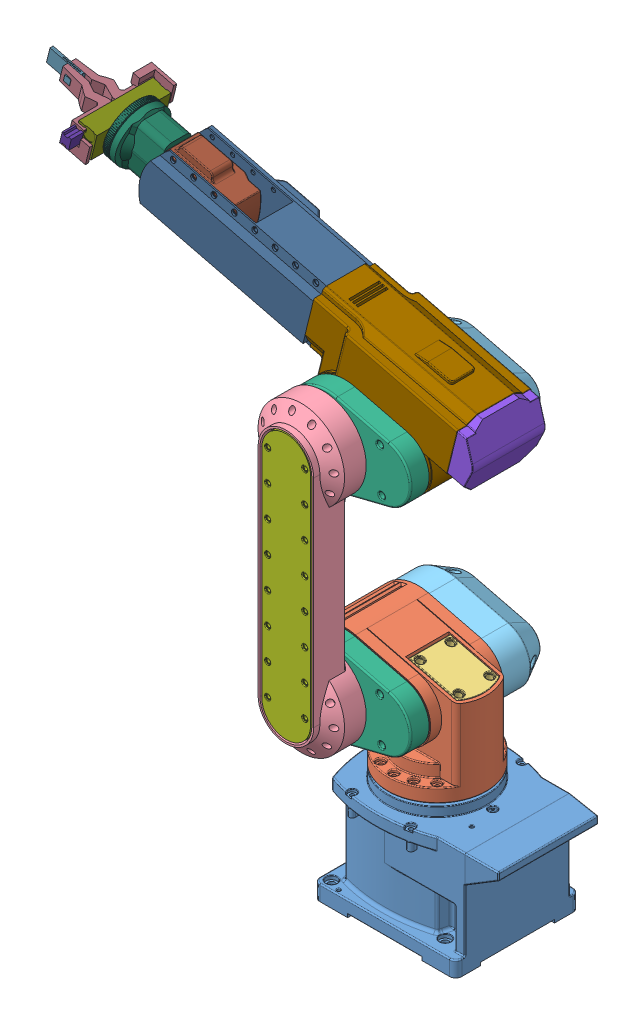
SolidWorks assembly Movable_assembly, configuration Default. Lengths in mm.
Overall size (813.38 886.02 303.42).
21 component instances, 17 part files, 61 mates.
Components (placement in the parent):
- Base-1: Base [Default] at (40.6048 41.5807 232.9888) size (280 185 200)
- Joint_1-1: Joint_1 [Default] at (58.3613 353.1317 232.9888) size (240 189 160)
- Joint_1_top_cap-1: Joint_1_top_cap [Default] at (60.6594 336.5807 232.9888) x (1 0 0) z (0 1 0) size (91.2 70 52.23)
- Joint_2-1: Joint_2 [Default] at (-31.634 665.5321 237.1035) x (0 -0.999953 -0.009698) z (0.003009 -0.009698 0.999948) size (490.3 140.11 64.56)
- Joint_1_right_cap-1: Joint_1_right_cap [Default] at (58.5861 41.5807 232.9888) x (0.999948 0.000764 -0.010154) z (0.010154 0.000008 0.999948) size (207.37 139.74 83.67)
- Joint_1_left_cap-1: Joint_1_left_cap [Default] at (58.5861 41.5807 232.9888) x (0.999948 0.000764 -0.010154) z (0.010154 0.000008 0.999948) size (205.37 137 45.97)
- joint_2_cap-1: joint_2_cap [Default] at (-285.7576 162.4328 232.9888) x (0.296333 -0.955031 -0.010154) z (0.003009 -0.009698 0.999948) size (415.27 184.72 18.75)
- Joint_3_cap^industry_robot_arm_3-1: Joint_3_cap^industry_robot_arm_3 [Default] at (285.08 198.5959 233.9888) x (0.970756 -0.239852 -0.010154) z (0.009858 -0.002436 0.999948) size (35.03 98.08 118.33)
- Joint_1_left_cap-2: Joint_1_left_cap [Default] at (58.5861 391.5643 232.9888) x (0.999948 0.000764 -0.010154) z (0.010154 0.000008 0.999948) size (205.37 137 45.97)
- Joint_1_right_cap-2: Joint_1_right_cap [Default] at (58.5861 391.5643 232.9888) x (0.999948 0.000764 -0.010154) z (0.010154 0.000008 0.999948) size (207.37 139.74 83.67)
- Joint_3-1: Joint_3 [Default] at (14.2411 648.346 236.7544) x (0.970756 -0.239852 -0.010154) z (0.009858 -0.002436 0.999948) size (270.42 212 122.27)
- Joint_3_front^industry_robot_arm_3-1: Joint_3_front^industry_robot_arm_3 [Default] at (-188.0196 914.7128 232.7268) x (0.970807 -0.239864 0) z (0 0 -1) size (280 99.67 120)
- joint_4^industry_robot_arm_3-1: joint_4^industry_robot_arm_3 [Default] at (-600.5154 840.3358 232.7268) x (-0.970807 0.239864 0) z (0 0 -1) size (126.86 92 60)
- Joint_3_top_cap^industry_robot_arm_3-1: Joint_3_top_cap^industry_robot_arm_3 [Default] at (518.3873 1141.5812 232.7268) x (0.970807 -0.239864 0) z (0 0 -1) size (97 20 57)
- Gripper_left^industry_robot_arm_3-1: Gripper_left^industry_robot_arm_3 [Default] at (467.2414 797.4566 88.5598) x (0.970807 -0.239864 0) z (0 0 -1) size (105.79 39 65)
- Gripper_right_grip^industry_robot_arm_3-1: Gripper_right_grip^industry_robot_arm_3 [Default] at (-1362.2348 1602.1194 -1819.7851) x (0.954279 -0.23578 0.183739) z (0.178375 -0.044072 -0.982975) size (52.87 24 20.92)
- joint_4_front^industry_robot_arm_3-1: joint_4_front^industry_robot_arm_3 [Default] at (-385.304 920.4982 389.4249) x (0 0 1) z (0.970807 -0.239864 0) size (88 88 70)
- joint_4_super_front^industry_robot_arm_3-1: joint_4_super_front^industry_robot_arm_3 [Default] at (-457.7741 793.9494 -121.3208) x (0 0 1) z (-0.970807 0.239864 0) size (120 40 40)
- joint_4_super_front_middle^industry_robot_arm_3-1: joint_4_super_front_middle^industry_robot_arm_3 [Default] at (-435.1377 966.8623 647.8138) x (0 0 -1) z (-0.970807 0.239864 0) size (160 18 25)
- Gripper_left^industry_robot_arm_3-2: Gripper_left^industry_robot_arm_3 [Default] at (399.422 522.9698 371.8138) x (0.970807 -0.239864 0) z (0 0 1) size (105.79 39 65)
- Gripper_right_grip^industry_robot_arm_3-2: Gripper_right_grip^industry_robot_arm_3 [Default] at (-1594.2874 662.9283 2280.1586) x (0.954279 -0.23578 -0.183739) z (0.178375 -0.044072 0.982975) size (52.87 24 20.92)
Mates (geometry in assembly coordinates):
- Coincident1: coincident anti-aligned: plane of Base-1 through (58.3613 216.5807 232.9888) normal (0 1 0); plane of Joint_1-1 through (58.3613 216.5807 232.9888) normal (0 -1 0)
- Concentric1: concentric anti-aligned: cylinder of Base-1 through (58.3613 216.5807 232.9888) axis (0 1 0) radius 70; cylinder of Joint_1-1 through (58.3613 242.5807 232.9888) axis (0 -1 0) radius 69
- Coincident2: coincident anti-aligned: plane of Joint_1-1 through (58.3613 336.5807 232.9888) normal (0 1 0); plane of Joint_1_top_cap-1 through (60.6594 336.5807 232.9888) normal (0 -1 0)
- Concentric2: concentric aligned: cylinder of Joint_1-1 through (58.3613 405.5807 232.9888) axis (0 -1 0) radius 75; cylinder of Joint_1_top_cap-1 through (58.3613 490.3724 232.9888) axis (0 -1 0) radius 75.4393
- Parallel1: parallel anti-aligned: plane of Joint_1-1 through (42.1565 405.5807 267.9888) normal (1 0 0); plane of Joint_1_top_cap-1 through (45.9545 490.3724 199.4888) normal (-1 0 0)
- Concentric3: concentric aligned: cylinder of Joint_1-1 through (58.3613 335.5807 272.9888) axis (0 0 -1) radius 48.4134; cylinder of Joint_1_left_cap-1 through (58.3613 335.5807 322.9888) axis (0 0 -1) radius 46.9225
- Concentric4: concentric anti-aligned: cylinder of Joint_1-1 through (58.3613 335.5807 272.9888) axis (0 0 -1) radius 48.4134; cylinder of Joint_1_right_cap-1 through (58.3613 335.5807 92.9888) axis (0 0 1) radius 46.9225
- Coincident4: coincident anti-aligned: plane of Joint_1-1 through (58.3613 353.1317 172.9888) normal (0 0 -1); plane of Joint_1_right_cap-1 through (58.3613 335.5807 172.9888) normal (0 0 1)
- Parallel2: parallel aligned: plane of Joint_1-1 through (65.887 383.5905 272.9888) normal (0.239864 0.970807 0); plane of Joint_1_right_cap-1 through (-14.8877 402.0123 92.9888) normal (0.239864 0.970807 0)
- Coincident5: coincident anti-aligned: plane of Joint_1-1 through (58.3613 353.1317 292.9888) normal (0 0 1); plane of Joint_1_left_cap-1 through (58.3613 335.5807 292.9888) normal (0 0 -1)
- Concentric5: concentric aligned: cylinder of Joint_1-1 through (58.3613 335.5807 272.9888) axis (0 0 -1) radius 48.4134; cylinder of Joint_1_left_cap-1 through (58.3613 335.5807 322.9888) axis (0 0 -1) radius 46.9225
- Parallel3: parallel aligned: plane of Joint_1-1 through (65.887 383.5905 272.9888) normal (0.239864 0.970807 0); plane of Joint_1_left_cap-1 through (69.6164 381.1333 322.9888) normal (0.239864 0.970807 0)
- Coincident6: coincident anti-aligned: plane of Joint_2-1 through (-31.634 335.5119 327.9888) normal (0 0 -1); plane of Joint_1_left_cap-1 through (-31.634 335.5119 327.9888) normal (0 0 1)
- Concentric6: concentric aligned: cylinder of Joint_2-1 through (-31.634 335.5119 337.9888) axis (0 0 -1) radius 30; cylinder of Joint_1_left_cap-1 through (-31.634 335.5119 337.9888) axis (0 0 -1) radius 30
- Concentric7: concentric anti-aligned: cylinder of Joint_2-1 through (-31.634 335.5119 372.9888) axis (0 0 1) radius 42; cylinder of joint_2_cap-1 through (-31.634 335.5119 387.5288) axis (0 0 -1) radius 39.5
- Concentric8: concentric anti-aligned: cylinder of Joint_2-1 through (-31.634 685.4954 372.9888) axis (0 0 1) radius 42; cylinder of joint_2_cap-1 through (-31.634 685.4954 387.5288) axis (0 0 -1) radius 39.5
- Coincident7: coincident anti-aligned: plane of Joint_2-1 through (-31.634 685.4954 372.9888) normal (0 0 1); plane of joint_2_cap-1 through (-31.634 335.5119 372.9888) normal (0 0 -1)
- Concentric9: concentric aligned: cylinder of Joint_2-1 through (-31.634 685.4954 337.9888) axis (0 0 -1) radius 30; cylinder of Joint_1_left_cap-2 through (-31.634 685.4954 337.9888) axis (0 0 -1) radius 30
- Coincident8: coincident anti-aligned: plane of Joint_2-1 through (-31.634 685.4954 327.9888) normal (0 0 -1); plane of Joint_1_left_cap-2 through (-31.634 685.4954 327.9888) normal (0 0 1)
- Coincident9: coincident anti-aligned: plane of Joint_3_cap^industry_robot_arm_3-1 through (153.4742 780.9574 263.176) normal (-0.970807 0.239864 0); plane of Joint_3-1 through (129.8476 685.333 172.9888) normal (0.970807 -0.239864 0)
- Coincident10: coincident aligned: plane of Joint_3_cap^industry_robot_arm_3-1 through (187.8122 774.0184 204.6587) normal (0.239864 0.970807 0); plane of Joint_3-1 through (-35.4705 829.1864 177.9888) normal (0.239864 0.970807 0)
- Coincident11: coincident aligned: plane of Joint_3_cap^industry_robot_arm_3-1 through (185.0538 762.8541 292.9888) normal (0 0 1); plane of Joint_3-1 through (58.3613 685.5642 292.9888) normal (0 0 1)
- Concentric10: concentric anti-aligned: cylinder of Joint_1_left_cap-2 through (58.3613 685.5642 322.9888) axis (0 0 -1) radius 46.9225; cylinder of Joint_3-1 through (58.3613 685.5642 172.9888) axis (0 0 1) radius 46.9225
- Coincident12: coincident anti-aligned: plane of Joint_1_left_cap-2 through (58.3613 685.5642 292.9888) normal (0 0 -1); plane of Joint_3-1 through (58.3613 685.5642 292.9888) normal (0 0 1)
- Concentric11: concentric anti-aligned: cylinder of Joint_1_left_cap-2 through (-31.3184 685.4956 322.9888) axis (0 0 -1) radius 68.5; cylinder of Joint_3-1 through (-31.3184 685.4956 172.9888) axis (0 0 1) radius 68.5
- Concentric12: concentric aligned: cylinder of Joint_1_right_cap-2 through (-31.3184 685.4956 92.9888) axis (0 0 1) radius 68.5; cylinder of Joint_3-1 through (-31.3184 685.4956 172.9888) axis (0 0 1) radius 68.5
- Concentric13: concentric aligned: cylinder of Joint_1_right_cap-2 through (58.3613 685.5642 92.9888) axis (0 0 1) radius 46.9225; cylinder of Joint_3-1 through (58.3613 685.5642 172.9888) axis (0 0 1) radius 46.9225
- Coincident13: coincident anti-aligned: plane of Joint_1_right_cap-2 through (58.3613 685.5642 172.9888) normal (0 0 1); plane of Joint_3-1 through (58.3613 685.5642 172.9888) normal (0 0 -1)
- Coincident19: coincident anti-aligned: plane of Joint_3_front^industry_robot_arm_3-1 through (-218.3075 792.128 232.7268) normal (-0.239864 -0.970807 0); plane of Joint_3_top_cap^industry_robot_arm_3-1 through (394.6276 640.6859 232.7268) normal (0.239864 0.970807 0)
- Distance3: distance = 1.5 mm anti-aligned: plane of Joint_3_front^industry_robot_arm_3-1 through (-212.8637 790.783 262.7268) normal (0.970807 -0.239864 0); plane of Joint_3_top_cap^industry_robot_arm_3-1 through (-216.2047 771.0071 261.2268) normal (-0.970807 0.239864 0)
- Distance4: distance = 1.5 mm anti-aligned: plane of Joint_3_top_cap^industry_robot_arm_3-1 through (-216.2047 771.0071 204.2268) normal (0 0 -1); plane of Joint_3_front^industry_robot_arm_3-1 through (-212.8637 790.783 202.7268) normal (0 0 1)
- Concentric14: concentric anti-aligned: cylinder of Joint_3_front^industry_robot_arm_3-1 through (-326.0038 847.8276 202.7268) axis (0 0 1) radius 30; cylinder of joint_4^industry_robot_arm_3-1 through (-326.0038 847.8276 262.7268) axis (0 0 -1) radius 30
- Coincident22: coincident anti-aligned: plane of Joint_3_front^industry_robot_arm_3-1 through (-481.1136 939.1221 202.7268) normal (0 0 1); plane of joint_4^industry_robot_arm_3-1 through (-600.5154 840.3358 202.7268) normal (0 0 -1)
- Coincident23: coincident anti-aligned: plane of joint_4^industry_robot_arm_3-1 through (-392.0827 788.8368 232.7268) normal (-0.970807 0.239864 0); plane of joint_4_front^industry_robot_arm_3-1 through (-361.0338 914.5016 389.4249) normal (0.970807 -0.239864 0)
- Coincident24: coincident aligned: plane of joint_4^industry_robot_arm_3-1 through (-257.9339 789.8062 202.7268) normal (-0.239864 -0.970807 0); plane of joint_4_front^industry_robot_arm_3-1 through (-379.2847 819.7892 202.7268) normal (-0.239864 -0.970807 0)
- Coincident25: coincident anti-aligned: plane of joint_4^industry_robot_arm_3-1 through (-370.9462 874.3829 247.7268) normal (0 0 1); plane of joint_4_front^industry_robot_arm_3-1 through (-378.1421 845.2587 247.7268) normal (0 0 -1)
- Parallel4: parallel aligned: plane of joint_4^industry_robot_arm_3-1 through (-257.9339 789.8062 202.7268) normal (-0.239864 -0.970807 0); plane of Joint_3_top_cap^industry_robot_arm_3-1 through (389.8303 621.2697 232.7268) normal (-0.239864 -0.970807 0)
- Coincident27: coincident anti-aligned: plane of joint_4_front^industry_robot_arm_3-1 through (-414.4282 927.6941 389.4249) normal (-0.970807 0.239864 0); plane of joint_4_super_front^industry_robot_arm_3-1 through (-448.0661 791.5507 -121.3208) normal (0.970807 -0.239864 0)
- Coincident28: coincident anti-aligned: plane of joint_4_front^industry_robot_arm_3-1 through (-431.5365 858.4512 247.7268) normal (0.239864 0.970807 0); plane of joint_4_super_front^industry_robot_arm_3-1 through (-431.5365 858.4512 247.7268) normal (-0.239864 -0.970807 0)
- Coincident29: coincident anti-aligned: plane of joint_4_front^industry_robot_arm_3-1 through (-431.5365 858.4512 217.7268) normal (0 0 1); plane of joint_4_super_front^industry_robot_arm_3-1 through (-431.5365 858.4512 217.7268) normal (0 0 -1)
- Coincident30: coincident anti-aligned: plane of joint_4_super_front^industry_robot_arm_3-1 through (-466.9968 796.2281 -121.3208) normal (-0.970807 0.239864 0); plane of joint_4_super_front_middle^industry_robot_arm_3-1 through (-425.4296 964.4637 647.8138) normal (0.970807 -0.239864 0)
- Coincident31: coincident anti-aligned: plane of joint_4_super_front^industry_robot_arm_3-1 through (-448.0686 872.8366 227.7268) normal (0.239864 0.970807 0); plane of joint_4_super_front_middle^industry_robot_arm_3-1 through (-448.0686 872.8366 227.7268) normal (-0.239864 -0.970807 0)
- Coincident32: coincident anti-aligned: plane of joint_4_super_front^industry_robot_arm_3-1 through (-445.6699 882.5447 237.7268) normal (0 0 -1); plane of joint_4_super_front_middle^industry_robot_arm_3-1 through (-448.0686 872.8366 237.7268) normal (0 0 1)
- Coincident34: coincident anti-aligned: plane of Gripper_left^industry_robot_arm_3-1 through (-527.4746 892.456 217.6468) normal (0.239864 0.970807 0); plane of Gripper_right_grip^industry_robot_arm_3-1 through (-537.1826 894.8547 217.6468) normal (-0.239864 -0.970807 0)
- Coincident37: coincident anti-aligned: plane of Gripper_left^industry_robot_arm_3-1 through (-506.0596 904.6761 227.6468) normal (0 0 1); plane of Gripper_right_grip^industry_robot_arm_3-1 through (-1362.2348 1602.1194 227.6468) normal (0 0 -1)
- Coincident38: coincident anti-aligned: plane of Gripper_left^industry_robot_arm_3-1 through (-537.1826 894.8547 217.6468) normal (0.970807 -0.239864 0); plane of Gripper_right_grip^industry_robot_arm_3-1 through (-537.1826 894.8547 217.6468) normal (-0.970807 0.239864 0)
- Coincident40: coincident anti-aligned: plane of Gripper_left^industry_robot_arm_3-1 through (-473.2982 874.95 167.6468) normal (0.970807 -0.239864 0); plane of joint_4_super_front_middle^industry_robot_arm_3-1 through (-449.6998 970.4603 647.8138) normal (-0.970807 0.239864 0)
- Coincident41: coincident anti-aligned: plane of Gripper_left^industry_robot_arm_3-1 through (-464.0162 875.2318 167.6468) normal (0.239864 0.970807 0); plane of joint_4_super_front_middle^industry_robot_arm_3-1 through (-468.8703 876.4311 312.7268) normal (-0.239864 -0.970807 0)
- Coincident42: coincident anti-aligned: plane of Gripper_left^industry_robot_arm_3-2 through (-511.8163 881.3767 232.7268) normal (0 0 -1); plane of Gripper_right_grip^industry_robot_arm_3-2 through (-1594.2874 662.9283 232.7268) normal (0 0 1)
- Coincident43: coincident anti-aligned: plane of Gripper_left^industry_robot_arm_3-2 through (-525.0759 902.1641 242.7268) normal (-0.239864 -0.970807 0); plane of Gripper_right_grip^industry_robot_arm_3-2 through (-534.784 904.5627 242.7268) normal (0.239864 0.970807 0)
- Coincident44: coincident anti-aligned: plane of Gripper_left^industry_robot_arm_3-2 through (-525.0759 902.1641 242.7268) normal (-0.970807 0.239864 0); plane of Gripper_right_grip^industry_robot_arm_3-2 through (-525.0759 902.1641 242.7268) normal (0.970807 -0.239864 0)
- Coincident45: coincident anti-aligned: plane of joint_4_super_front_middle^industry_robot_arm_3-1 through (-449.6998 970.4603 647.8138) normal (-0.970807 0.239864 0); plane of Gripper_left^industry_robot_arm_3-2 through (-468.9806 892.4245 292.7268) normal (0.970807 -0.239864 0)
- Coincident47: coincident anti-aligned: plane of joint_4_super_front_middle^industry_robot_arm_3-1 through (-468.8703 876.4311 312.7268) normal (-0.239864 -0.970807 0); plane of Gripper_left^industry_robot_arm_3-2 through (-468.8703 876.4311 292.7268) normal (0.239864 0.970807 0)
- Concentric15: concentric aligned: cylinder of Joint_3-1 through (-110.5689 796.2379 232.9888) axis (0.970807 -0.239864 0) radius 30; cylinder of Joint_3_front^industry_robot_arm_3-1 through (-110.5689 796.2379 232.9888) axis (0.970807 -0.239864 0) radius 30
- Coincident48: coincident anti-aligned: plane of Joint_3-1 through (-110.5689 796.2379 232.9888) normal (-0.970807 0.239864 0); plane of Joint_3_front^industry_robot_arm_3-1 through (-110.5689 796.2379 232.9888) normal (0.970807 -0.239864 0)
- Parallel6: parallel aligned: plane of Base-1 through (188.3613 131.5807 317.9888) normal (0 0 1); plane of Joint_1-1 through (58.3613 353.1317 272.9888) normal (0 0 1)
- Parallel7: parallel aligned: plane of Base-1 through (188.3613 66.5807 132.9888) normal (1 0 0); plane of Joint_2-1 through (13.366 685.4954 337.9888) normal (1 0 0)
- Parallel8: parallel aligned: plane of Joint_1-1 through (65.887 383.5905 272.9888) normal (0.239864 0.970807 0); plane of Joint_3-1 through (-35.4705 829.1864 177.9888) normal (0.239864 0.970807 0)
- Parallel9: parallel aligned: plane of Joint_3-1 through (-35.4705 829.1864 177.9888) normal (0.239864 0.970807 0); plane of Joint_3_front^industry_robot_arm_3-1 through (-88.9078 842.217 182.7268) normal (0.239864 0.970807 0)
- Coincident49: coincident anti-aligned: plane of Gripper_right_grip^industry_robot_arm_3-1 through (-1362.2348 1602.1194 230.1868) normal (0 0 1); plane of Gripper_right_grip^industry_robot_arm_3-2 through (-1594.2874 662.9283 230.1868) normal (0 0 -1)
- Coincident50: coincident anti-aligned: plane of joint_4_super_front^industry_robot_arm_3-1 through (-461.9735 902.024 292.7268) normal (0 0 1); plane of Gripper_left^industry_robot_arm_3-2 through (399.422 522.9698 292.7268) normal (0 0 -1)
